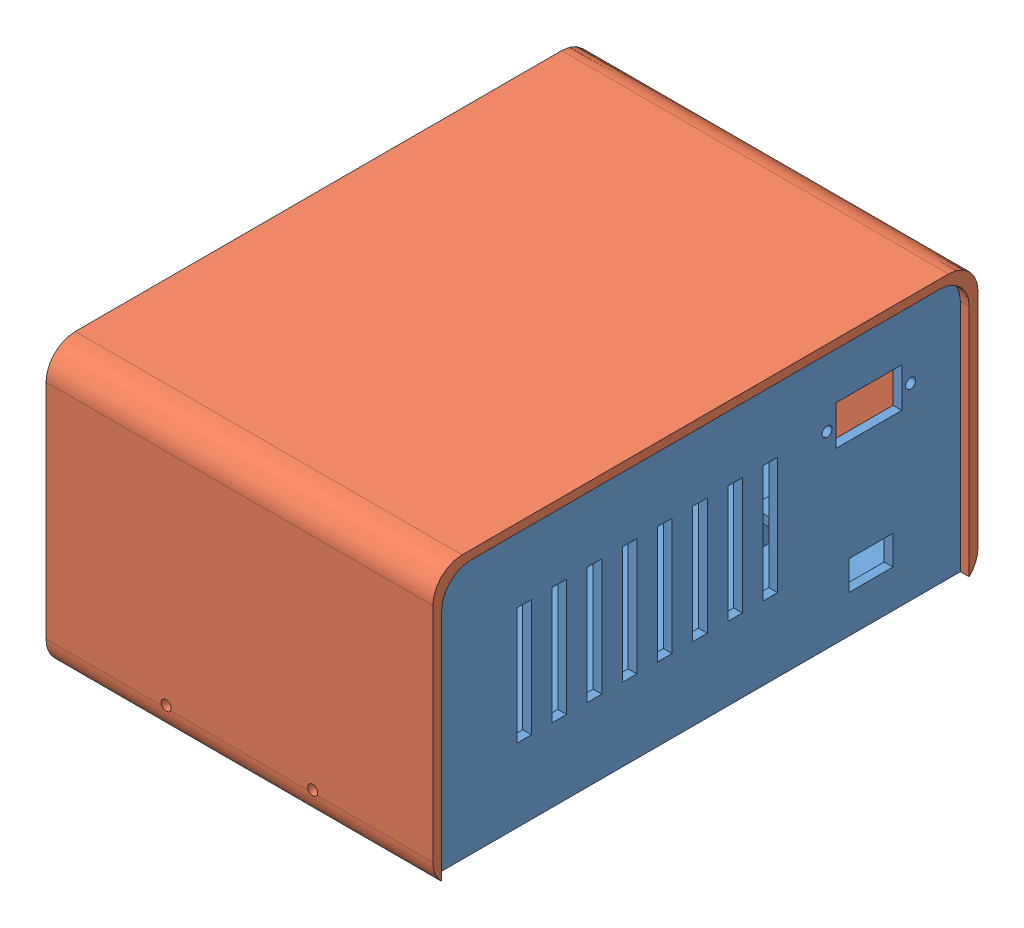
SolidWorks assembly Assem2, configuration Default. Lengths in mm.
Overall size (132 93 186).
2 component instances, 2 part files, 3 mates.
Components (placement in the parent):
- Assem2-1: Assem2 [Default] at (7.3173 -12.32 4.5088) size (128 90 180)
- Top_Part-1: Top_Part [Default] at (-9.8015 134.426 239.5935) x (0 0 1) z (-1 0 0) size (186 93 132)
Mates (geometry in assembly coordinates):
- Coincident1: coincident: plane of Assem2-1 through (-6.8015 131.426 59.5935) normal (0 0 -1); plane of Top_Part-1 through (-9.8015 134.426 59.5935) normal (0 0 1)
- Concentric1: concentric: cylinder of Assem2-1 through (31.1985 49.426 229.5935) axis (0 0 1) radius 1.7; cylinder of Top_Part-1 through (31.1985 49.426 242.5935) axis (0 0 -1) radius 1.7
- Concentric2: concentric anti-aligned: cylinder of Assem2-1 through (81.1985 49.426 229.5935) axis (0 0 1) radius 1.7; cylinder of Top_Part-1 through (81.1985 49.426 242.5935) axis (0 0 -1) radius 1.7
